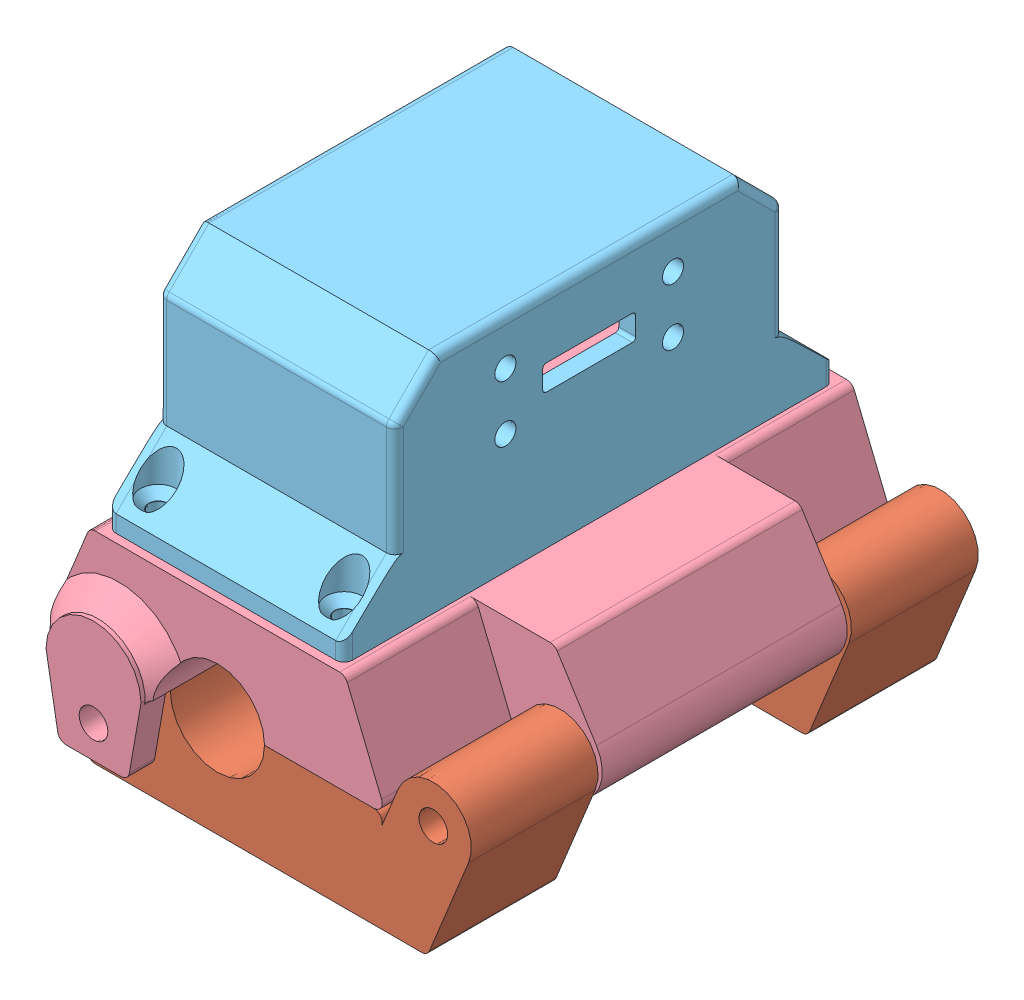
SolidWorks assembly light_sens_assem, configuration Default. Lengths in mm.
Overall size (77.75 89.22 66).
5 component instances, 5 part files, 1 mates.
Components (placement in the parent):
- spectral_chip-1: spectral_chip [Default] at origin size (25.7 4 28)
- spectral_shield-1: spectral_shield [Default] at origin size (77.75 89.22 60)
- spec_top_shield-1: spec_top_shield [Default] at origin size (26.15 9.94 29)
- spec_clip_led+ethernet-1: spec_clip_led+ethernet [Default] at origin size (49.83 20.65 66)
- spec_clip_ledeth_cap-2: spec_clip_ledeth_cap [Default] at (0 21.8715 0) size (28 31.1 58)
Mates (geometry in assembly coordinates):
- Coincident1: coincident aligned: circle of spec_clip_led+ethernet-1; circle of spec_clip_ledeth_cap-2
